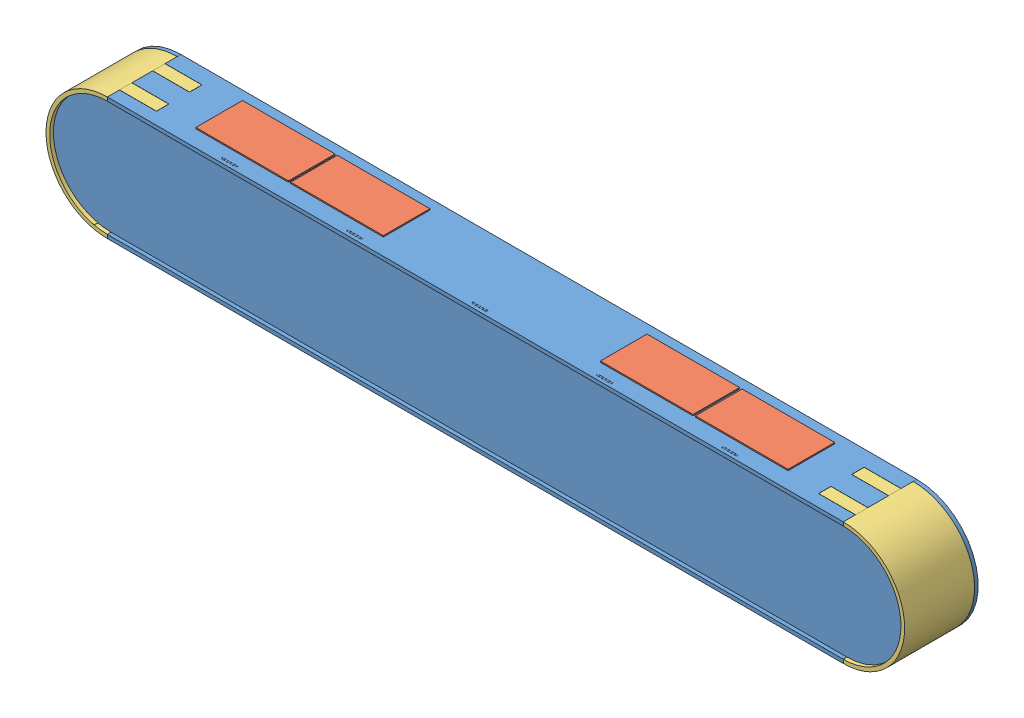
SolidWorks assembly Assem2, configuration Default. Lengths in mm.
Overall size (700 101 60).
8 component instances, 3 part files, 18 mates.
Components (placement in the parent):
- Assem1-1: Assem1 [Default] at (410.585 333.6547 480.0278) size (700 100 60)
  - partFull-1: partFull [Default] at (-199.8938 48.0418 42.8423) size (700 100 60)
- ustKapaklar8-1: ustKapaklar8 [Default] at (-41.9088 381.6965 522.7702) size (75.5 2 38)
- ustKapaklar8-2: ustKapaklar8 [Default] at (288.0912 381.6965 522.7702) size (75.5 2 38)
- ustKapaklar8-3: ustKapaklar8 [Default] at (-119.2088 381.6965 522.7702) size (75.5 2 38)
- ustKapaklar8-4: ustKapaklar8 [Default] at (210.5912 381.6965 522.7702) size (75.5 2 38)
- yanKapaklar4-1: yanKapaklar4 [Default] at (210.6912 381.6965 522.8702) size (80 100 57)
- yanKapaklar4-2: yanKapaklar4 [Default] at (210.6912 381.6965 522.8702) x (-1 0 0) z (0 0 1) size (80 100 57)
Mates (geometry in assembly coordinates):
- Coincident1: coincident anti-aligned: plane of Assem1-1/partFull-1 through (-89.3088 381.6965 525.8702) normal (0 0 1); plane of yanKapaklar4-1 through (210.6912 381.6965 525.8702) normal (0 0 -1)
- Coincident2: coincident anti-aligned: plane of Assem1-1/partFull-1 through (-89.3088 381.6965 522.8702) normal (-1 0 0); plane of yanKapaklar4-1 through (-89.3088 381.6965 522.8702) normal (1 0 0)
- Coincident3: coincident aligned: plane of Assem1-1/partFull-1 through (-89.3088 431.6965 582.8702) normal (0 1 0); plane of yanKapaklar4-1 through (-89.3088 431.6965 582.8702) normal (0 1 0)
- Coincident4: coincident aligned: plane of Assem1-1/partFull-1 through (-89.3088 431.6965 582.8702) normal (0 1 0); plane of yanKapaklar4-2 through (510.6912 431.6965 582.8702) normal (0 1 0)
- Coincident5: coincident anti-aligned: plane of Assem1-1/partFull-1 through (-89.3088 381.6965 525.8702) normal (0 0 1); plane of yanKapaklar4-2 through (210.6912 381.6965 525.8702) normal (0 0 -1)
- Coincident6: coincident anti-aligned: plane of Assem1-1/partFull-1 through (510.6912 381.6965 522.8702) normal (1 0 0); plane of yanKapaklar4-2 through (510.6912 381.6965 522.8702) normal (-1 0 0)
- Coincident7: coincident: plane of Assem1-1/partFull-1 through (-89.3088 431.6965 582.8702) normal (0 1 0); plane of ustKapaklar8-3 through (-119.2088 431.6965 522.7702) normal (0 -1 0)
- Coincident8: coincident: plane of Assem1-1/partFull-1 through (-89.3088 431.6965 582.8702) normal (0 1 0); plane of ustKapaklar8-1 through (-41.9088 431.6965 528.2509) normal (0 -1 0)
- Coincident9: coincident anti-aligned: plane of Assem1-1/partFull-1 through (-89.3088 431.6965 582.8702) normal (0 1 0); plane of ustKapaklar8-4 through (210.5912 431.6965 522.7702) normal (0 -1 0)
- Coincident10: coincident: plane of Assem1-1/partFull-1 through (-89.3088 431.6965 582.8702) normal (0 1 0); plane of ustKapaklar8-2 through (288.0912 431.6965 522.7702) normal (0 -1 0)
- Coincident11: coincident anti-aligned: plane of Assem1-1/partFull-1 through (300.5912 421.6965 532.8702) normal (1 0 0); plane of ustKapaklar8-4 through (300.5912 430.6965 532.7702) normal (-1 0 0)
- Coincident12: coincident anti-aligned: plane of Assem1-1/partFull-1 through (300.6912 421.6965 532.7702) normal (0 0 1); plane of ustKapaklar8-4 through (300.5912 430.6965 532.7702) normal (0 0 -1)
- Coincident14: coincident: plane of Assem1-1/partFull-1 through (378.0912 431.6965 532.7702) normal (1 0 0); plane of ustKapaklar8-2 through (378.0912 430.6965 532.7702) normal (-1 0 0)
- Coincident16: coincident anti-aligned: plane of Assem1-1/partFull-1 through (300.6912 421.6965 532.7702) normal (0 0 1); plane of ustKapaklar8-2 through (378.0912 430.6965 532.7702) normal (0 0 -1)
- Coincident17: coincident: plane of Assem1-1/partFull-1 through (43.2912 431.6965 532.7702) normal (-1 0 0); plane of ustKapaklar8-3 through (43.2912 430.6965 532.7702) normal (1 0 0)
- Coincident18: coincident anti-aligned: plane of Assem1-1/partFull-1 through (-29.3088 421.6965 532.7702) normal (0 0 1); plane of ustKapaklar8-3 through (-29.2088 430.6965 532.7702) normal (0 0 -1)
- Coincident19: coincident: plane of Assem1-1/partFull-1 through (48.0912 431.6965 532.7702) normal (1 0 0); plane of ustKapaklar8-1 through (48.0912 430.6965 538.2509) normal (-1 0 0)
- Coincident20: coincident anti-aligned: plane of Assem1-1/partFull-1 through (-29.3088 421.6965 532.7702) normal (0 0 1); plane of ustKapaklar8-1 through (48.0912 430.6965 532.7702) normal (0 0 -1)
